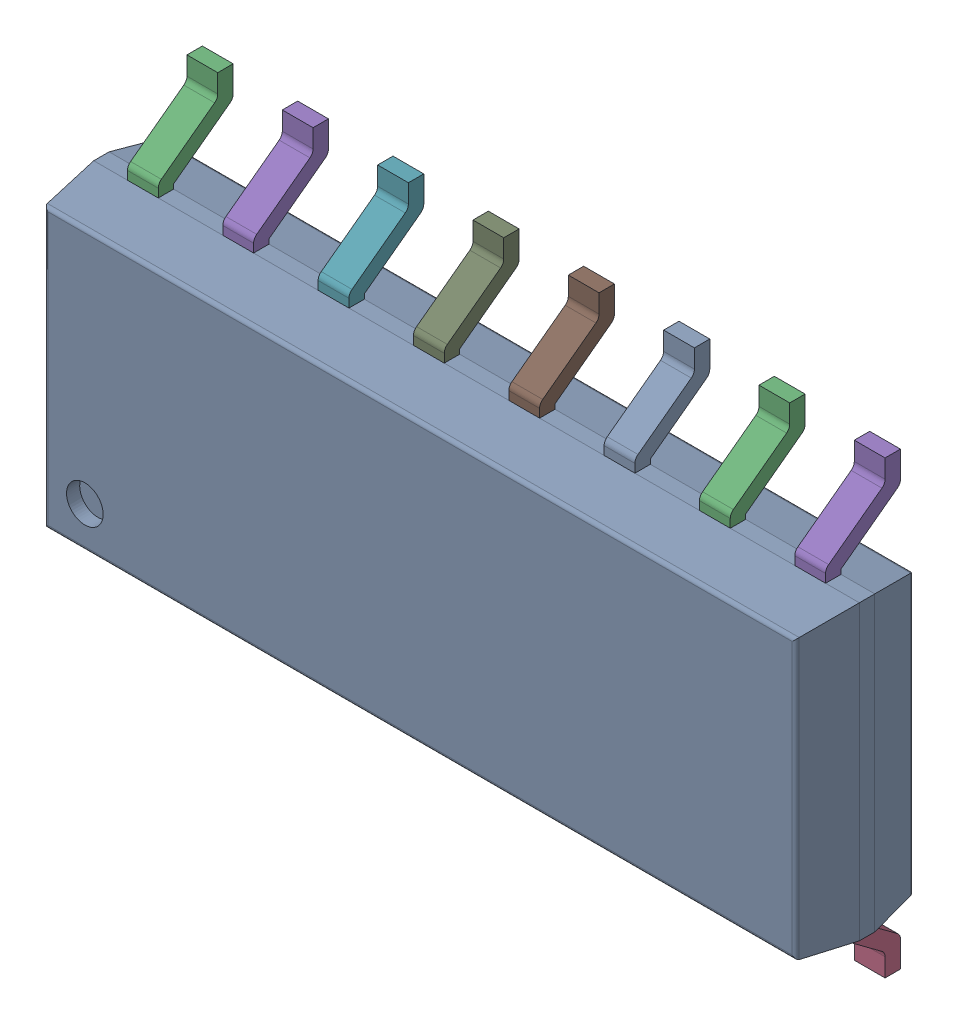
SolidWorks assembly IC16_1.step, configuration Default. Lengths in mm.
Overall size (10.2 6 1.75).
3 component instances, 2 part files, 0 mates.
Components (placement in the parent):
- 6348803008_1.step-3: 6348803008_1.step [Default] at (520.065 271.75 0) x (0 1 0) z (0 0 1) size (6 10.2 1.75)
  - Body-14_1.step-8: Body-14_1.step [Default] at origin size (3.9 10.2 1.57)
  - PinsArrayLR-15_1.step-8: PinsArrayLR-15_1.step [Default] at origin size (6 9.3 1)
